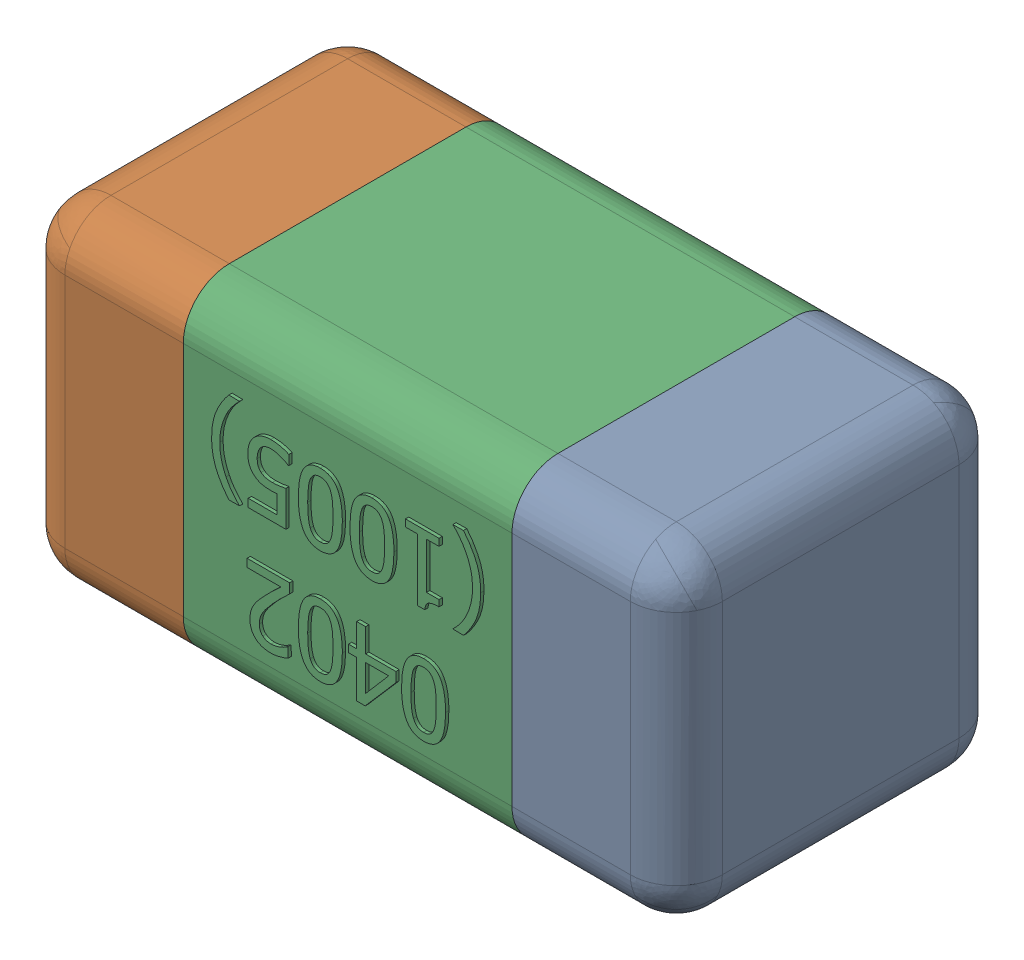
SolidWorks assembly C1, configuration Standard. Lengths in mm.
Overall size (1.01 0.51 0.51).
4 component instances, 3 part files, 0 mates.
Components (placement in the parent):
- C1-subassembly-1-1: C1-subassembly-1 [Standard] at (5.8999 4.6 0) x (-1 0 0) z (0 0 1) size (1.01 0.51 0.51)
  - User Library-0402_Cap-1: User Library-0402_Cap [Standard] at origin size (0.26 0.51 0.51)
  - User Library-0402_Cap-1-1: User Library-0402_Cap-1 [Standard] at origin size (0.26 0.5 0.51)
  - User Library-0402_Cap-2-1: User Library-0402_Cap-2 [Standard] at origin size (0.5 0.5 0.51)
